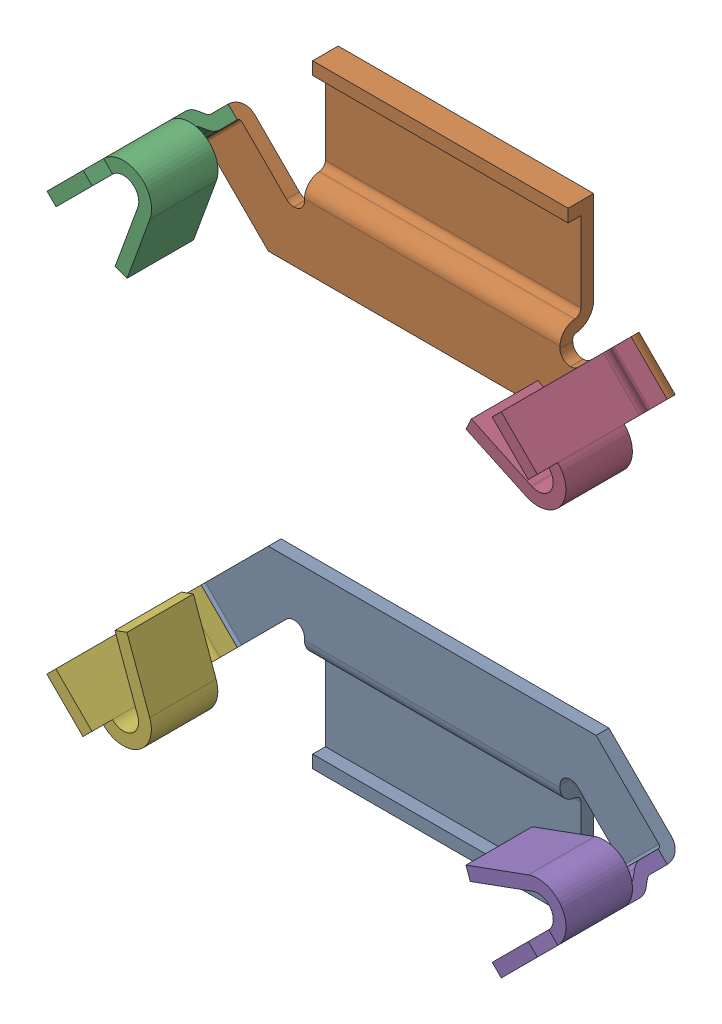
SolidWorks assembly Leadframe_bended, configuration Default. Lengths in mm.
Overall size (11.55 12 3.98).
6 component instances, 6 part files, 0 mates.
Components (placement in the parent):
- Leadframe-1: Leadframe [Default] at origin size (9.3 3.5 0.71)
- Leadframe_2-1: Leadframe_2 [Default] at origin size (9.3 3.5 0.71)
- PIN_1-1: PIN_1 [Default] at (-4.2957 4.2957 -5.8993) x (0.5 0.5 -0.707107) z (0.707107 -0.707107 0) size (2.61 2.72 1.6)
- PIN_2-1: PIN_2 [Default] at (4.2957 4.2957 -5.8993) x (0.5 -0.5 0.707107) z (-0.707107 -0.707107 0) size (2.71 2.61 1.51)
- PIN_3-1: PIN_3 [Default] at (4.2957 -4.2957 -5.8993) x (0.5 0.5 0.707107) z (-0.707107 0.707107 0) size (2.72 2.61 1.6)
- PIN_4-1: PIN_4 [Default] at (-4.2957 -4.2957 -5.8993) x (0.5 -0.5 -0.707107) z (0.707107 0.707107 0) size (2.61 2.72 1.6)
